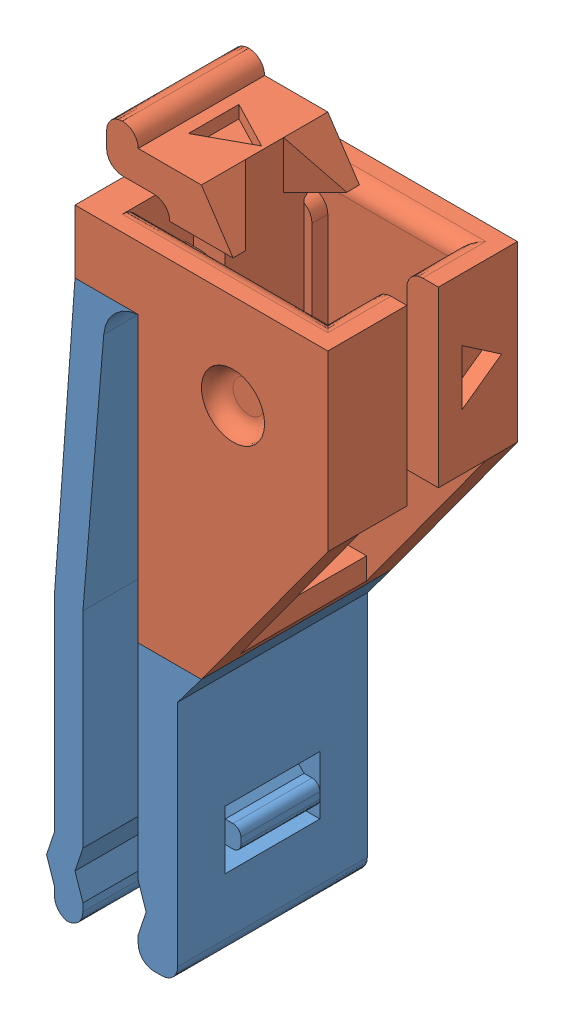
SolidWorks assembly NeedleClip-Assembly_16-20G, configuration Default. Lengths in mm.
Overall size (17.8 43.6 12).
2 component instances, 2 part files, 5 mates.
Components (placement in the parent):
- NeedleGrabber_16-20G-1: NeedleGrabber_16-20G [Default] at (1.8381 19.0841 16.5771) x (0 1 0) z (0 0 1) size (35.5 9.8 12)
- SensorHolder_2.0-1: SensorHolder_2.0 [Default] at (4.1059 1.0841 20.5456) size (16 26.1 12)
Mates (geometry in assembly coordinates):
- Coincident1: coincident anti-aligned: plane of ? through (4.1059 -0.1403 20.5456) normal (0 -1 0); plane of NeedleGrabber_16-20G-1 through (1.8381 -0.1403 28.5771) normal (0 1 0)
- Coincident2: coincident aligned: plane of ? through (-2.1619 1.8597 28.5771) normal (0 0 1); plane of NeedleGrabber_16-20G-1 through (1.8381 17.8597 28.5771) normal (0 0 1)
- Coincident3: coincident anti-aligned: plane of NeedleGrabber_16-20G-1 through (1.8381 1.0841 28.5771) normal (0 1 0); plane of SensorHolder_2.0-1 through (4.1059 1.0841 20.5456) normal (0 -1 0)
- Coincident4: coincident aligned: plane of NeedleGrabber_16-20G-1 through (1.8381 19.0841 16.5771) normal (0 0 -1); plane of SensorHolder_2.0-1 through (-2.1619 3.0841 16.5771) normal (0 0 -1)
- Coincident5: coincident aligned: plane of NeedleGrabber_16-20G-1 through (1.8381 1.0841 28.5771) normal (-1 0 0); plane of SensorHolder_2.0-1 through (1.8381 6.0841 20.5456) normal (-1 0 0)
